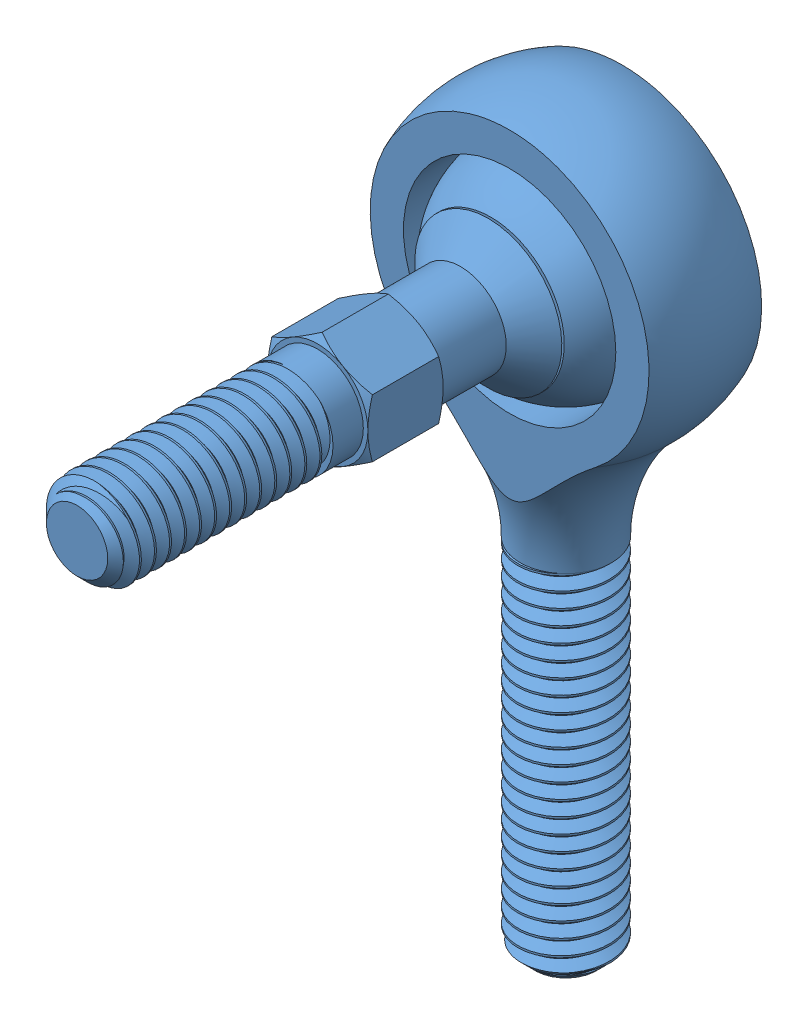
SolidWorks assembly 60645K211_STEEL BALL JOINT ROD END Assem, configuration Default. Lengths in mm.
Overall size (15.88 39.82 29.86).
3 component instances, 1 part files, 3 mates.
Components (placement in the parent):
- 60645K211_STEEL BALL JOINT ROD END-1: 60645K211_STEEL BALL JOINT ROD END [60645K211] at origin size (15.88 39.82 17.68)
- 60645K211_STEEL BALL JOINT ROD END-2: 60645K211_STEEL BALL JOINT ROD END [Ball] at origin size (11.1 11.1 18.68)
- 60645K211_STEEL BALL JOINT ROD END-3: 60645K211_STEEL BALL JOINT ROD END [Stud] at origin size (7.76 35.63 29.86)
Mates (geometry in assembly coordinates):
- Coincident1: coincident: point of 60645K211_STEEL BALL JOINT ROD END-1; point of 60645K211_STEEL BALL JOINT ROD END-2
- Concentric1: concentric aligned: cylinder of 60645K211_STEEL BALL JOINT ROD END-2 through (0 12.7 -3.9688) axis (0 0 1) radius 2.413; cylinder of 60645K211_STEEL BALL JOINT ROD END-3 through (0 12.7 -3.9688) axis (0 0 1) radius 2.413
- Coincident2: coincident aligned: plane of 60645K211_STEEL BALL JOINT ROD END-2 through (-7.9375 20.6375 -3.9688) normal (0 0 -1); plane of 60645K211_STEEL BALL JOINT ROD END-3 through (0 12.7 -3.9688) normal (0 0 -1)
